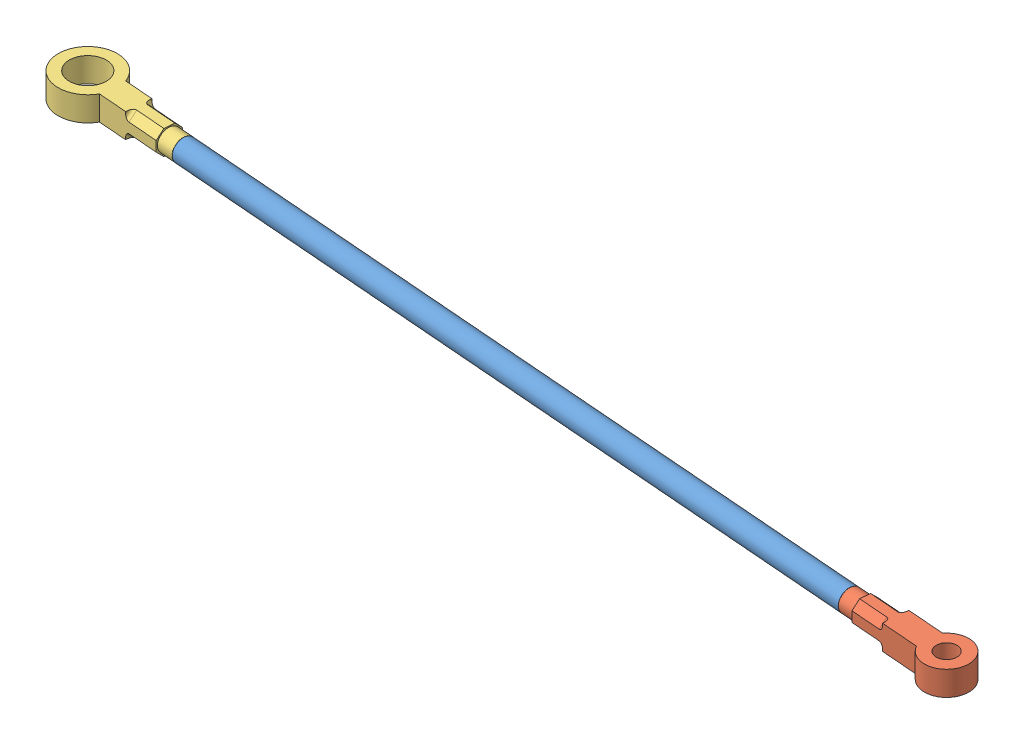
SolidWorks assembly Assieme3, configuration Default. Lengths in mm.
Overall size (133.62 3.3 18.44).
5 component instances, 3 part files, 0 mates.
Components (placement in the parent):
- Assieme5^Assieme3-1: Assieme5^Assieme3 [Default] at origin size (133.62 3.3 18.44) (virtual)
  - Copia di Assieme4^Assieme5_Assieme3-1: Copia di Assieme4^Assieme5_Assieme3 [Default] at (127.8021 8.7602 8.6279) x (0.996917 0 0.078459) z (-0.078459 0 0.996917) size (133.4 3.3 8) (virtual)
    - link_c-1: link_c [Default] at (-50.5388 -2.2091 100) size (100 3 3)
    - assembly - EYE END-1: assembly - EYE END [Default] at (104.2788 -2.2091 100) size (17.2 3.3 6)
    - assembly - EYE START_5mmdiam-1: assembly - EYE START_5mmdiam [Default] at (-99.7965 -2.2091 100) x (-1 0 0) z (0 0 -1) size (18.2 3.3 8)
